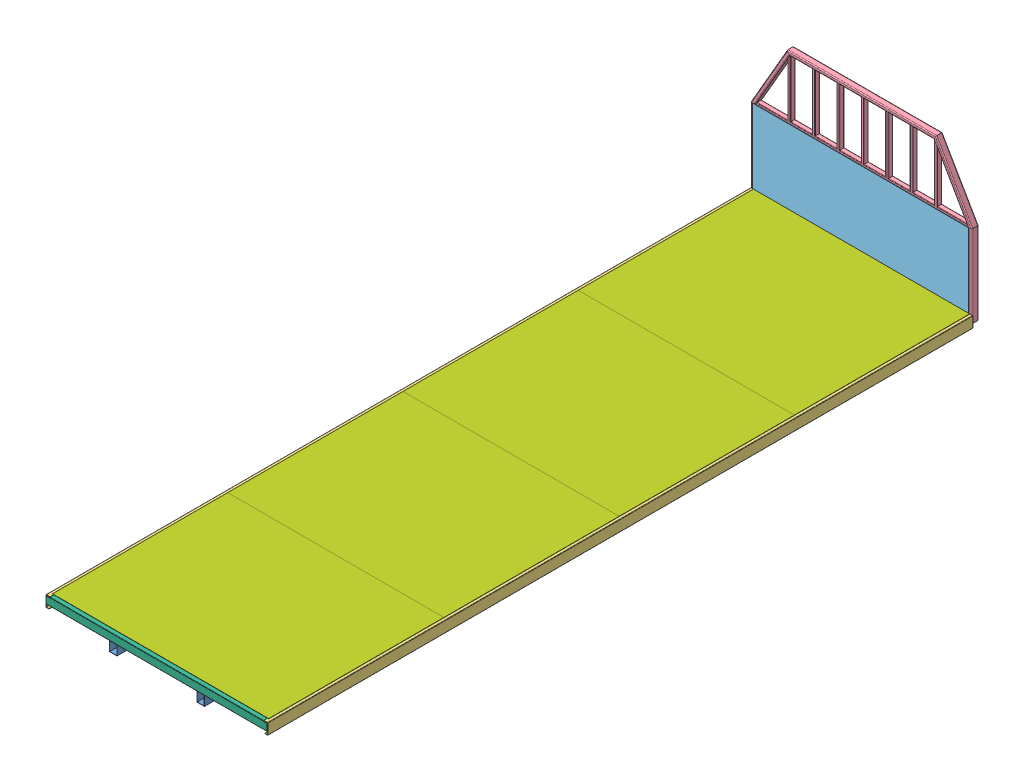
SolidWorks assembly FLAT DECK, configuration Default. Lengths in mm.
Overall size (2360.56 1645 7574.02).
25 component instances, 7 part files, 30 mates.
Components (placement in the parent):
- RUNNER-1: RUNNER [Default<As Machined>] at (2732.5653 4026.6389 1965.6519) size (80 105 7500)
- RUNNER-2: RUNNER [Default<As Machined>] at (3662.5653 4026.6389 1965.6519) size (80 105 7500)
- CROSS MEMBER-2: CROSS MEMBER [Default] at (2022.0053 4083.1389 9231.6519) x (0 0 -1) z (1 0 0) size (44 79 2350.56)
- CROSS MEMBER-5: CROSS MEMBER [Default] at (2022.0053 4083.1389 8701.6519) x (0 0 -1) z (1 0 0) size (44 79 2350.56)
- CROSS MEMBER-6: CROSS MEMBER [Default] at (2022.0053 4083.1389 8171.6519) x (0 0 -1) z (1 0 0) size (44 79 2350.56)
- CROSS MEMBER-7: CROSS MEMBER [Default] at (2022.0053 4083.1389 7641.6519) x (0 0 -1) z (1 0 0) size (44 79 2350.56)
- CROSS MEMBER-8: CROSS MEMBER [Default] at (2022.0053 4083.1389 7111.6519) x (0 0 -1) z (1 0 0) size (44 79 2350.56)
- CROSS MEMBER-9: CROSS MEMBER [Default] at (2022.0053 4083.1389 6581.6519) x (0 0 -1) z (1 0 0) size (44 79 2350.56)
- CROSS MEMBER-10: CROSS MEMBER [Default] at (2022.0053 4083.1389 6051.6519) x (0 0 -1) z (1 0 0) size (44 79 2350.56)
- CROSS MEMBER-11: CROSS MEMBER [Default] at (2022.0053 4083.1389 5521.6519) x (0 0 -1) z (1 0 0) size (44 79 2350.56)
- CROSS MEMBER-12: CROSS MEMBER [Default] at (2022.0053 4083.1389 4991.6519) x (0 0 -1) z (1 0 0) size (44 79 2350.56)
- CROSS MEMBER-13: CROSS MEMBER [Default] at (2022.0053 4083.1389 4461.6519) x (0 0 -1) z (1 0 0) size (44 79 2350.56)
- CROSS MEMBER-14: CROSS MEMBER [Default] at (2022.0053 4083.1389 3931.6519) x (0 0 -1) z (1 0 0) size (44 79 2350.56)
- CROSS MEMBER-15: CROSS MEMBER [Default] at (2022.0053 4083.1389 3401.6519) x (0 0 -1) z (1 0 0) size (44 79 2350.56)
- CROSS MEMBER-16: CROSS MEMBER [Default] at (2022.0053 4083.1389 2871.6519) x (0 0 -1) z (1 0 0) size (44 79 2350.56)
- COMMING-1: COMMING [Default] at (2020.0053 4048.1389 1965.6519) size (44 118 7500)
- COMMING-2: COMMING [Default] at (4372.5653 4048.1389 9465.7319) x (-1 0 0) z (0 0 -1) size (44 118 7500)
- HEAD FRAME ASSEMBLY-2: HEAD FRAME ASSEMBLY [Default] at (2325.3755 3556.332 165.3626) size (2350.56 1540 74)
  - HEAD FRAME-1: HEAD FRAME [Default<As Machined>] at (-289.3702 542.8069 1765.3693) size (2350.56 1540 70)
  - HB-1: HB [Default] at (-289.3702 555.8069 1804.3693) size (2300 840 4)
- REAR CROSS MEMBER-2: REAR CROSS MEMBER [Default] at (2022.3653 4083.1389 9465.7519) size (2350.2 81.5 49)
- DECK SHEET-4: DECK SHEET [Default] at (2046.4653 4164.6389 9426.1319) x (1 0 0) z (0 1 0) size (2300 1864.1 2.5)
- DECK SHEET-5: DECK SHEET [Default] at (2046.4653 4164.6389 7562.0319) x (1 0 0) z (0 1 0) size (2300 1864.1 2.5)
- DECK SHEET-6: DECK SHEET [Default] at (2046.4653 4164.6389 5697.9319) x (1 0 0) z (0 1 0) size (2300 1864.1 2.5)
- DECK SHEET-7: DECK SHEET [Default] at (2046.4653 4164.6389 3833.8319) x (1 0 0) z (0 1 0) size (2300 1864.1 2.5)
Mates (geometry in assembly coordinates):
- Distance1: distance = 850 mm anti-aligned: plane of RUNNER-1 through (2772.5653 4076.6389 9465.6519) normal (1 0 0); plane of RUNNER-2 through (3622.5653 4076.6389 9465.6519) normal (-1 0 0)
- Coincident30: coincident aligned: plane of RUNNER-1 through (2695.0653 4079.1389 9465.6519) normal (0 1 0); plane of RUNNER-2 through (3625.0653 4079.1389 9465.6519) normal (0 1 0)
- Coincident5: coincident aligned: plane of RUNNER-1 through (2732.5653 4026.6389 1965.6519) normal (0 0 -1); plane of RUNNER-2 through (3662.5653 4026.6389 1965.6519) normal (0 0 -1)
- Coincident7: coincident anti-aligned: plane of RUNNER-2 through (3625.0653 4079.1389 9465.6519) normal (0 1 0); plane of CROSS MEMBER-2 through (4372.5653 4079.1389 9231.6519) normal (0 -1 0)
- Distance4: distance = 230 mm aligned: plane of CROSS MEMBER-2 through (4372.5653 4158.1389 9235.6519) normal (0 0 1); plane of RUNNER-2 through (3662.5653 4026.6389 9465.6519) normal (0 0 1)
- Coincident12: coincident: line of CROSS MEMBER-10 through (4370.5653 4158.1389 6053.6519) axis (-1 0 0); plane of COMMING-1 through (2060.0053 4158.1389 9465.6519) normal (0 -1 0)
- Distance6: distance = 230 mm: plane of CROSS MEMBER-2 through (4372.5653 4158.1389 9235.6519) normal (0 0 1); line of COMMING-1 through (2018.0053 4048.2389 9465.6519) axis (0 1 0)
- Distance7: distance = 2 mm: plane of COMMING-1 through (2020.0053 4158.1389 9465.6519) normal (1 0 0); line of CROSS MEMBER-2 through (2022.0053 4156.1389 9233.6519) axis (0 -1 0)
- Coincident26: coincident anti-aligned: plane of RUNNER-1 through (2695.0653 4079.1389 9465.6519) normal (0 1 0); plane of HEAD FRAME ASSEMBLY-2/HEAD FRAME-1 through (4346.5607 4079.1389 1905.7319) normal (0 -1 0)
- Coincident27: coincident aligned: plane of COMMING-1 through (2016.0053 4158.1389 9465.6519) normal (-1 0 0); plane of HEAD FRAME ASSEMBLY-2/HEAD FRAME-1 through (2016.0053 4099.1389 1905.7319) normal (-1 0 0)
- Distance11: distance = 670 mm: plane of RUNNER-2 through (3702.5653 4076.6389 9465.6519) normal (1 0 0); line of CROSS MEMBER-2 through (4372.5653 4083.2389 9233.6519) axis (0 1 0)
- Distance12: distance = 230.08 mm: plane of CROSS MEMBER-2 through (4372.5653 4158.1389 9235.6519) normal (0 0 1); line of COMMING-2 through (4374.5653 4048.2389 9465.7319) axis (0 1 0)
- Coincident46: coincident: line of CROSS MEMBER-2 through (4372.5653 4083.2389 9233.6519) axis (0 1 0); plane of COMMING-2 through (4372.5653 4158.1389 1965.7319) normal (-1 0 0)
- Coincident49: coincident: line of COMMING-2 through (4374.5653 4048.2389 1965.7319) axis (0 1 0); plane of HEAD FRAME ASSEMBLY-2/HEAD FRAME-1 through (4336.5607 4949.1389 1965.7319) normal (0 0 1)
- Coincident63: coincident anti-aligned: plane of RUNNER-1 through (2695.0653 4079.1389 9465.6519) normal (0 1 0); plane of REAR CROSS MEMBER-2 through (4372.5653 4079.1389 9465.7519) normal (0 -1 0)
- Coincident70: coincident anti-aligned: plane of COMMING-2 through (4372.5653 4158.1389 1965.7319) normal (-1 0 0); plane of REAR CROSS MEMBER-2 through (4372.5653 4160.6389 9465.6519) normal (1 0 0)
- Coincident71: coincident aligned: line of RUNNER-2 through (3702.5653 4079.1389 9465.6519) axis (-1 0 0); line of REAR CROSS MEMBER-2 through (4372.5653 4079.1389 9465.6519) axis (-1 0 0)
- Coincident105: coincident anti-aligned: plane of HEAD FRAME ASSEMBLY-2/HB-1 through (2036.0053 4112.1389 1969.7319) normal (0 0 1); plane of DECK SHEET-7 through (2046.4653 4162.1389 1969.7319) normal (0 0 -1)
- Coincident106: coincident anti-aligned: plane of COMMING-2 through (4332.5653 4162.1389 1965.7319) normal (0 1 0); plane of DECK SHEET-7 through (2046.4653 4162.1389 3833.8319) normal (0 -1 0)
- Coincident107: coincident anti-aligned: line of DECK SHEET-6 through (4346.4653 4164.6389 3833.8319) axis (-1 0 0); line of DECK SHEET-7 through (2046.4653 4164.6389 3833.8319) axis (1 0 0)
- Coincident108: coincident anti-aligned: line of DECK SHEET-5 through (4346.4653 4164.6389 5697.9319) axis (-1 0 0); line of DECK SHEET-6 through (2046.4653 4164.6389 5697.9319) axis (1 0 0)
- Coincident109: coincident anti-aligned: line of DECK SHEET-4 through (4346.4653 4164.6389 7562.0319) axis (-1 0 0); line of DECK SHEET-5 through (2046.4653 4164.6389 7562.0319) axis (1 0 0)
- Coincident110: coincident anti-aligned: plane of COMMING-2 through (4332.5653 4162.1389 1965.7319) normal (0 1 0); plane of DECK SHEET-6 through (2046.4653 4162.1389 5697.9319) normal (0 -1 0)
- Coincident111: coincident anti-aligned: plane of COMMING-2 through (4332.5653 4162.1389 1965.7319) normal (0 1 0); plane of DECK SHEET-5 through (2046.4653 4162.1389 7562.0319) normal (0 -1 0)
- Coincident112: coincident anti-aligned: plane of COMMING-2 through (4332.5653 4162.1389 1965.7319) normal (0 1 0); plane of DECK SHEET-4 through (2046.4653 4162.1389 9426.1319) normal (0 -1 0)
- Coincident114: coincident aligned: line of DECK SHEET-6 through (4346.4653 4164.6389 5697.9319) axis (0 0 -1); line of DECK SHEET-7 through (4346.4653 4164.6389 3833.8319) axis (0 0 -1)
- Coincident115: coincident aligned: line of DECK SHEET-5 through (4346.4653 4164.6389 7562.0319) axis (0 0 -1); line of DECK SHEET-6 through (4346.4653 4164.6389 5697.9319) axis (0 0 -1)
- Coincident118: coincident aligned: line of DECK SHEET-4 through (4346.4653 4164.6389 9426.1319) axis (0 0 -1); line of DECK SHEET-5 through (4346.4653 4164.6389 7562.0319) axis (0 0 -1)
- Distance23: distance = 26 mm: plane of DECK SHEET-7 through (4346.4653 4162.1389 3833.8319) normal (1 0 0); line of COMMING-2 through (4372.4653 4162.1389 1967.7319) axis (0 0 1)
- Coincident121: coincident anti-aligned: plane of COMMING-1 through (2060.0053 4162.1389 9465.6519) normal (0 1 0); plane of DECK SHEET-7 through (2046.4653 4162.1389 3833.8319) normal (0 -1 0)
